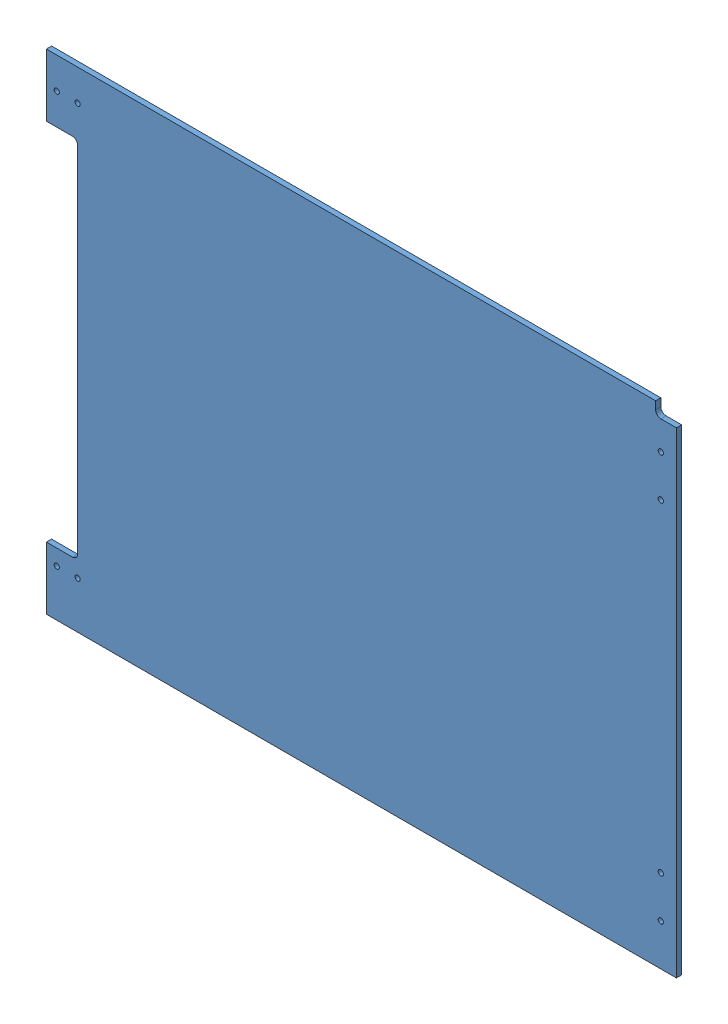
SolidWorks assembly GE-19079-Left-Red, configuration Default. Lengths in mm.
Overall size (768.35 596.9 56.73).
2 component instances, 2 part files, 3 mates.
Components (placement in the parent):
- GE-19079-1: GE-19079 [GE-19079] at origin size (768.35 596.9 6.35)
- GE-19079-Left-Red-Vinyl-1: GE-19079-Left-Red-Vinyl [Notched] at (0 0 -0.127) size (768.35 596.9 0.13)
Mates (geometry in assembly coordinates):
- Coincident1: coincident: plane of assembly; plane of assembly; plane of GE-19079-1 through (0 0 0) normal (0 0 -1); plane of GE-19079-Left-Red-Vinyl-1 through (0 0 0) normal (0 0 1)
- Coincident2: coincident: plane of assembly; plane of assembly; plane of GE-19079-1 through (-368.3 298.45 6.35) normal (0 1 0); plane of GE-19079-Left-Red-Vinyl-1 through (-368.3 298.45 0) normal (0 1 0)
- Coincident3: coincident: plane of assembly; plane of assembly; plane of GE-19079-1 through (368.3 -298.45 6.35) normal (1 0 0); plane of GE-19079-Left-Red-Vinyl-1 through (368.3 -298.45 0) normal (1 0 0)
